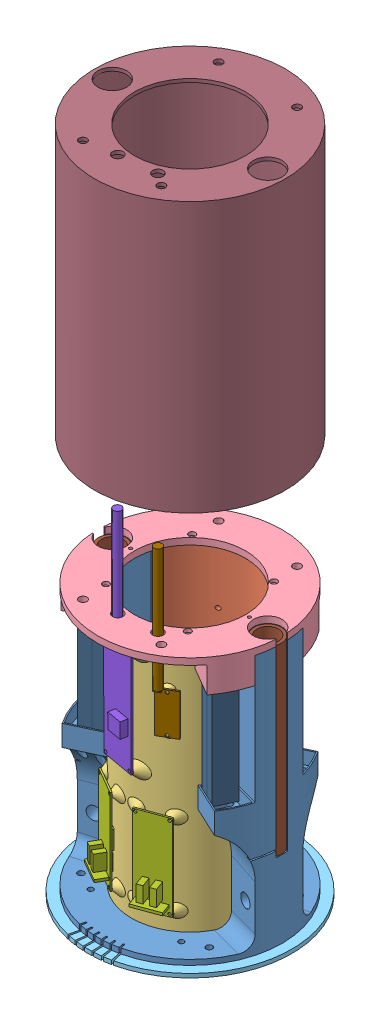
SolidWorks assembly Electronics Bay Assembly, configuration Default. Lengths in mm.
Overall size (198.12 649.43 198.12).
23 component instances, 13 part files, 55 mates.
Components (placement in the parent):
- Base 2-3: Base 2 [Default] at origin size (179.07 252.73 179.07)
- Recovery Slide ALARA-3: Recovery Slide ALARA [Default] at (0 5.08 0) size (111.51 248.38 47.72)
- Recovery Slide General-3: Recovery Slide General [Default] at (0 5.08 0) x (-1 0 0) z (0 0 -1) size (111.51 248.38 48.37)
- Top Part-7: Top Part [Default] at (0 259.08 0) x (-1 0 0) z (0 0 1) size (178.71 31.75 179.07)
- Centering Ring-3: Centering Ring [Baby Shark Recovery Centering Ring] at (0 -1.905 0) x (-1 0 0) z (0 0 -1) size (198.12 3.81 198.12)
- ALARA PCB-4: ALARA PCB [Default] at (25 60.255 -62.484) x (-1 0 0) z (0 1 0) size (50 1.52 150)
- Eggtimer Proton-6: Eggtimer Proton [Default] at (20.327 62.2633 55.9361) x (0 1 0) z (0.939693 0 -0.34202) size (83.27 15.04 30.57)
- Eggtimer Proton-7: Eggtimer Proton [Default] at (-29.7314 62.2633 51.5566) x (0 1 0) z (0.866025 0 0.5) size (83.27 15.04 30.57)
- Eggtimer TRS Tracker-9: Eggtimer TRS Tracker [Default] at (-10.3007 182.8899 58.6168) x (0.000689 -1 0.000122) z (-0.984808 -0.0007 -0.173648) size (216.46 11.11 32.77)
- Telemetry Module-5: Telemetry Module [Default] at (29.7575 190.5032 51.5415) x (0 -1 0) z (-0.866025 0 0.5) size (161.4 7.84 19.04)
- Turnigy nano-tech 1200mAh 2S 15_25C Lipo 2-13: Turnigy nano-tech 1200mAh 2S 15_25C Lipo 2 [Default] at (-46.5329 252.73 35.0242) x (-0.422618 0 -0.906308) z (0 1 0) size (19.71 10.41 127.79)
- Turnigy nano-tech 1200mAh 2S 15_25C Lipo 2-14: Turnigy nano-tech 1200mAh 2S 15_25C Lipo 2 [Default] at (-55.9712 252.73 39.4254) x (-0.422618 0 -0.906308) z (0 1 0) size (19.71 10.41 127.79)
- Turnigy nano-tech 1200mAh 2S 15_25C Lipo 2-15: Turnigy nano-tech 1200mAh 2S 15_25C Lipo 2 [Default] at (65.4095 252.73 43.8265) x (0.422618 0 -0.906308) z (0 1 0) size (19.71 10.41 127.79)
- Turnigy nano-tech 1200mAh 2S 15_25C Lipo 2-16: Turnigy nano-tech 1200mAh 2S 15_25C Lipo 2 [Default] at (55.9712 252.73 39.4254) x (0.422618 0 -0.906308) z (0 1 0) size (19.71 10.41 127.79)
- Charge Tube-1: Charge Tube [Default] at (75.565 74.93 0) x (0.797278 0 0.603612) z (-0.603612 0 0.797278) size (26.67 177.8 26.67)
- Charge Tube-2: Charge Tube [Default] at (-75.565 74.93 0) x (-0.785022 0 0.619467) z (-0.619467 0 -0.785022) size (26.67 177.8 26.67)
- Turnigy nano-tech 1200mAh 2S 15_25C Lipo 2-17: Turnigy nano-tech 1200mAh 2S 15_25C Lipo 2 [Default] at (-54.8629 252.73 -17.1605) x (0.422618 0 -0.906308) z (0 1 0) size (19.71 10.41 127.79)
- Turnigy nano-tech 1200mAh 2S 15_25C Lipo 2-18: Turnigy nano-tech 1200mAh 2S 15_25C Lipo 2 [Default] at (-64.3012 252.73 -21.5617) x (0.422618 0 -0.906308) z (0 1 0) size (19.71 10.41 127.79)
- Turnigy nano-tech 1200mAh 2S 15_25C Lipo 2-19: Turnigy nano-tech 1200mAh 2S 15_25C Lipo 2 [Default] at (73.7395 252.73 -25.9628) x (-0.422618 0 -0.906308) z (0 1 0) size (19.71 10.41 127.79)
- Turnigy nano-tech 1200mAh 2S 15_25C Lipo 2-20: Turnigy nano-tech 1200mAh 2S 15_25C Lipo 2 [Default] at (64.3012 252.73 -21.5617) x (-0.422618 0 -0.906308) z (0 1 0) size (19.71 10.41 127.79)
- 97171A310_Brass Heat-Set Inserts for Plastic-1: 97171A310_Brass Heat-Set Inserts for Plastic [97171A310] at (-23.7651 232.2195 53.378) x (0.661787 -0.740554 0.116691) z (-0.729304 -0.671996 -0.128596) size (5.54 6.42 5.54)
- 97171A310_Brass Heat-Set Inserts for Plastic-2: 97171A310_Brass Heat-Set Inserts for Plastic [97171A310] at (-39.7766 249.3298 41.9158) x (0.543007 0 -0.839728) z (0.839728 0 0.543007) size (5.54 6.42 5.54)
- Ebay Hatch V2-2: Ebay Hatch V2 [Default] at (0 645.6163 0) x (-1 0 0) z (0 0 1) size (185.42 262.38 185.42)
Mates (geometry in assembly coordinates):
- Coincident130: coincident anti-aligned: plane of Base 2-3 through (0 252.73 0) normal (0 1 0); plane of Top Part-7 through (0 252.73 0) normal (0 -1 0)
- Coincident131: coincident anti-aligned: plane of Base 2-3 through (0 252.73 0) normal (0.258819 0 -0.965926); plane of Top Part-7 through (0 227.33 0) normal (-0.258819 0 0.965926)
- Coincident132: coincident anti-aligned: plane of Base 2-3 through (0 0 0) normal (0 -1 0); plane of Centering Ring-3 through (0 0 0) normal (0 1 0)
- Concentric76: concentric anti-aligned: cylinder of Base 2-3 through (44.0824 -7.1842 52.5353) axis (0 1 0) radius 2.54; cylinder of Centering Ring-3 through (44.0824 8.621 52.5353) axis (0 -1 0) radius 2.54
- Concentric77: concentric anti-aligned: cylinder of Base 2-3 through (0 5.08 0) axis (0 -1 0) radius 89.535; cylinder of Centering Ring-3 through (0 -3.81 0) axis (0 1 0) radius 99.06
- Concentric78: concentric aligned: cylinder of Base 2-3 through (0 5.08 0) axis (0 -1 0) radius 53.975; cylinder of Recovery Slide General-3 through (0 252.73 0) axis (0 -1 0) radius 53.975
- Coincident133: coincident anti-aligned: plane of Base 2-3 through (0 252.73 0) normal (-0.258819 0 0.965926); plane of Recovery Slide General-3 through (0 252.73 0) normal (0.258819 0 -0.965926)
- Coincident134: coincident anti-aligned: plane of Recovery Slide General-3 through (0 252.73 0) normal (0 1 0); plane of Top Part-7 through (0 252.73 0) normal (0 -1 0)
- Concentric79: concentric anti-aligned: cylinder of Base 2-3 through (0 5.08 0) axis (0 -1 0) radius 89.535; cylinder of Top Part-7 through (0 252.73 0) axis (0 1 0) radius 89.535
- Concentric80: concentric aligned: cylinder of Base 2-3 through (0 5.08 0) axis (0 -1 0) radius 53.975; cylinder of Recovery Slide ALARA-3 through (0 252.73 0) axis (0 -1 0) radius 53.975
- Coincident135: coincident anti-aligned: plane of Base 2-3 through (0 252.73 0) normal (-0.258819 0 -0.965926); plane of Recovery Slide ALARA-3 through (0 252.73 0) normal (0.258819 0 0.965926)
- Coincident136: coincident anti-aligned: plane of Recovery Slide ALARA-3 through (0 252.73 0) normal (0 1 0); plane of Top Part-7 through (0 252.73 0) normal (0 -1 0)
- Coincident158: coincident anti-aligned: plane of Recovery Slide ALARA-3 through (-22 202.255 -60.96) normal (0 0 -1); plane of ALARA PCB-4 through (25 60.255 -60.96) normal (0 0 1)
- Concentric97: concentric anti-aligned: cylinder of Recovery Slide ALARA-3 through (22 202.255 -13.2433) axis (0 0 -1) radius 2.0193; cylinder of ALARA PCB-4 through (22 202.255 -67.0095) axis (0 0 1) radius 1.6
- Coincident159: coincident anti-aligned: plane of Recovery Slide General-3 through (-41.086 101.6 45.001) normal (-0.5 0 0.866025); plane of Eggtimer Proton-7 through (-29.7314 62.2633 51.5566) normal (0.5 0 -0.866025)
- Concentric98: concentric aligned: cylinder of Recovery Slide General-3 through (19.0385 22.86 -6.8136) axis (-0.5 0 0.866025) radius 2.0193; cylinder of Eggtimer Proton-7 through (-16.3568 22.86 54.4929) axis (-0.5 0 0.866025) radius 1.4653
- Coincident160: coincident anti-aligned: plane of Recovery Slide General-3 through (8.0632 101.6 60.3998) normal (0.34202 0 0.939693); plane of Eggtimer Proton-6 through (20.327 62.2633 55.9361) normal (-0.34202 0 -0.939693)
- Concentric99: concentric aligned: cylinder of Recovery Slide General-3 through (-14.2405 22.86 -0.8791) axis (0.34202 0 0.939693) radius 2.0193; cylinder of Eggtimer Proton-6 through (6.6457 22.86 56.5053) axis (0.34202 0 0.939693) radius 1.4653
- Coincident161: coincident anti-aligned: plane of Recovery Slide General-3 through (-24.255 232.2195 56.1563) normal (-0.173648 0 0.984808); plane of Eggtimer TRS Tracker-9 through (-10.3007 182.8899 58.6168) normal (0.173648 0 -0.984808)
- Concentric100: concentric aligned: cylinder of Recovery Slide General-3 through (-14.6497 232.2195 1.6815) axis (-0.173648 0 0.984808) radius 2.0193; cylinder of Eggtimer TRS Tracker-9 through (-23.5252 232.2195 52.0174) axis (-0.173648 0 0.984808) radius 1.4859
- Coincident163: coincident anti-aligned: plane of Recovery Slide General-3 through (29.7575 208.28 51.5415) normal (0.5 0 0.866025); plane of Telemetry Module-5 through (29.7575 190.5032 51.5415) normal (-0.5 0 -0.866025)
- Concentric101: concentric aligned: cylinder of Recovery Slide General-3 through (-7.71 208.28 -13.3541) axis (0.5 0 0.866025) radius 2.0193; cylinder of Telemetry Module-5 through (27.6696 208.28 47.9251) axis (0.5 0 0.866025) radius 1.4764
- Coincident164: coincident anti-aligned: plane of Turnigy nano-tech 1200mAh 2S 15_25C Lipo 2-13 through (-55.9712 252.73 39.4254) normal (-0.906308 0 0.422618); plane of Turnigy nano-tech 1200mAh 2S 15_25C Lipo 2-14 through (-55.9712 252.73 39.4254) normal (0.906308 0 -0.422618)
- Coincident165: coincident aligned: plane of Turnigy nano-tech 1200mAh 2S 15_25C Lipo 2-13 through (-55.9712 252.73 39.4254) normal (0.422618 0 0.906308); plane of Turnigy nano-tech 1200mAh 2S 15_25C Lipo 2-14 through (-65.4095 252.73 43.8265) normal (0.422618 0 0.906308)
- Coincident166: coincident aligned: plane of Turnigy nano-tech 1200mAh 2S 15_25C Lipo 2-13 through (-55.9712 252.73 39.4254) normal (0 1 0); plane of Turnigy nano-tech 1200mAh 2S 15_25C Lipo 2-14 through (-65.4095 252.73 43.8265) normal (0 1 0)
- Coincident167: coincident aligned: plane of Turnigy nano-tech 1200mAh 2S 15_25C Lipo 2-15 through (55.9712 252.73 39.4254) normal (-0.422618 0 0.906308); plane of Turnigy nano-tech 1200mAh 2S 15_25C Lipo 2-16 through (46.5329 252.73 35.0242) normal (-0.422618 0 0.906308)
- Coincident168: coincident anti-aligned: plane of Turnigy nano-tech 1200mAh 2S 15_25C Lipo 2-15 through (55.9712 252.73 39.4254) normal (-0.906308 0 -0.422618); plane of Turnigy nano-tech 1200mAh 2S 15_25C Lipo 2-16 through (55.9712 252.73 39.4254) normal (0.906308 0 0.422618)
- Coincident169: coincident aligned: plane of Turnigy nano-tech 1200mAh 2S 15_25C Lipo 2-15 through (55.9712 252.73 39.4254) normal (0 1 0); plane of Turnigy nano-tech 1200mAh 2S 15_25C Lipo 2-16 through (46.5329 252.73 35.0242) normal (0 1 0)
- Coincident170: coincident anti-aligned: plane of Top Part-7 through (0 252.73 0) normal (0 -1 0); plane of Turnigy nano-tech 1200mAh 2S 15_25C Lipo 2-13 through (-55.9712 252.73 39.4254) normal (0 1 0)
- Coincident171: coincident anti-aligned: plane of Top Part-7 through (-3.226 227.33 -6.9182) normal (0.422618 0 0.906308); plane of Turnigy nano-tech 1200mAh 2S 15_25C Lipo 2-13 through (-64.3012 252.73 21.5617) normal (-0.422618 0 -0.906308)
- Coincident172: coincident anti-aligned: plane of Top Part-7 through (0 252.73 0) normal (0 -1 0); plane of Turnigy nano-tech 1200mAh 2S 15_25C Lipo 2-15 through (55.9712 252.73 39.4254) normal (0 1 0)
- Tangent6: tangent anti-aligned: cylinder of Recovery Slide General-3 through (0 252.73 0) axis (0 -1 0) radius 56.975; plane of Turnigy nano-tech 1200mAh 2S 15_25C Lipo 2-13 through (-46.5329 252.73 35.0242) normal (0.906308 0 -0.422618)
- Coincident174: coincident anti-aligned: plane of Top Part-7 through (3.226 227.33 -6.9182) normal (-0.422618 0 0.906308); plane of Turnigy nano-tech 1200mAh 2S 15_25C Lipo 2-16 through (54.8629 252.73 17.1605) normal (0.422618 0 -0.906308)
- Tangent7: tangent anti-aligned: cylinder of Recovery Slide General-3 through (0 252.73 0) axis (0 -1 0) radius 56.975; plane of Turnigy nano-tech 1200mAh 2S 15_25C Lipo 2-16 through (46.5329 252.73 35.0242) normal (-0.906308 0 -0.422618)
- Concentric102: concentric anti-aligned: cylinder of Base 2-3 through (75.565 74.93 0) axis (0 1 0) radius 13.97; cylinder of Charge Tube-1 through (75.565 252.73 0) axis (0 -1 0) radius 13.335
- Coincident175: coincident anti-aligned: plane of Base 2-3 through (0 74.93 0) normal (0 1 0); plane of Charge Tube-1 through (75.565 74.93 0) normal (0 -1 0)
- Concentric103: concentric anti-aligned: cylinder of Base 2-3 through (-75.565 74.93 0) axis (0 1 0) radius 13.97; cylinder of Charge Tube-2 through (-75.565 252.73 0) axis (0 -1 0) radius 13.335
- Coincident176: coincident anti-aligned: plane of Base 2-3 through (0 74.93 0) normal (0 1 0); plane of Charge Tube-2 through (-75.565 74.93 0) normal (0 -1 0)
- Coincident177: coincident anti-aligned: plane of Turnigy nano-tech 1200mAh 2S 15_25C Lipo 2-17 through (-64.3012 252.73 -21.5617) normal (-0.906308 0 -0.422618); plane of Turnigy nano-tech 1200mAh 2S 15_25C Lipo 2-18 through (-64.3012 252.73 -21.5617) normal (0.906308 0 0.422618)
- Coincident178: coincident aligned: plane of Turnigy nano-tech 1200mAh 2S 15_25C Lipo 2-17 through (-64.3012 252.73 -21.5617) normal (-0.422618 0 0.906308); plane of Turnigy nano-tech 1200mAh 2S 15_25C Lipo 2-18 through (-73.7395 252.73 -25.9628) normal (-0.422618 0 0.906308)
- Coincident179: coincident aligned: plane of Turnigy nano-tech 1200mAh 2S 15_25C Lipo 2-17 through (-64.3012 252.73 -21.5617) normal (0 1 0); plane of Turnigy nano-tech 1200mAh 2S 15_25C Lipo 2-18 through (-73.7395 252.73 -25.9628) normal (0 1 0)
- Coincident180: coincident anti-aligned: plane of Top Part-7 through (-3.226 227.33 6.9182) normal (0.422618 0 -0.906308); plane of Turnigy nano-tech 1200mAh 2S 15_25C Lipo 2-17 through (-64.3012 252.73 -21.5617) normal (-0.422618 0 0.906308)
- Tangent8: tangent anti-aligned: cylinder of Recovery Slide ALARA-3 through (0 252.73 0) axis (0 -1 0) radius 56.975; plane of Turnigy nano-tech 1200mAh 2S 15_25C Lipo 2-17 through (-54.8629 252.73 -17.1605) normal (0.906308 0 0.422618)
- Coincident181: coincident anti-aligned: plane of Top Part-7 through (0 252.73 0) normal (0 -1 0); plane of Turnigy nano-tech 1200mAh 2S 15_25C Lipo 2-18 through (-73.7395 252.73 -25.9628) normal (0 1 0)
- Coincident182: coincident anti-aligned: plane of Turnigy nano-tech 1200mAh 2S 15_25C Lipo 2-19 through (64.3012 252.73 -21.5617) normal (-0.906308 0 0.422618); plane of Turnigy nano-tech 1200mAh 2S 15_25C Lipo 2-20 through (64.3012 252.73 -21.5617) normal (0.906308 0 -0.422618)
- Coincident183: coincident aligned: plane of Turnigy nano-tech 1200mAh 2S 15_25C Lipo 2-19 through (64.3012 252.73 -21.5617) normal (0.422618 0 0.906308); plane of Turnigy nano-tech 1200mAh 2S 15_25C Lipo 2-20 through (54.8629 252.73 -17.1605) normal (0.422618 0 0.906308)
- Coincident184: coincident aligned: plane of Turnigy nano-tech 1200mAh 2S 15_25C Lipo 2-19 through (64.3012 252.73 -21.5617) normal (0 1 0); plane of Turnigy nano-tech 1200mAh 2S 15_25C Lipo 2-20 through (54.8629 252.73 -17.1605) normal (0 1 0)
- Coincident185: coincident anti-aligned: plane of Top Part-7 through (3.226 227.33 6.9182) normal (-0.422618 0 -0.906308); plane of Turnigy nano-tech 1200mAh 2S 15_25C Lipo 2-20 through (54.8629 252.73 -17.1605) normal (0.422618 0 0.906308)
- Coincident186: coincident anti-aligned: plane of Top Part-7 through (0 252.73 0) normal (0 -1 0); plane of Turnigy nano-tech 1200mAh 2S 15_25C Lipo 2-20 through (54.8629 252.73 -17.1605) normal (0 1 0)
- Tangent9: tangent anti-aligned: cylinder of Recovery Slide ALARA-3 through (0 252.73 0) axis (0 -1 0) radius 56.975; plane of Turnigy nano-tech 1200mAh 2S 15_25C Lipo 2-20 through (54.8629 252.73 -17.1605) normal (-0.906308 0 0.422618)
- Concentric104: concentric aligned: cylinder of Recovery Slide General-3 through (-39.7766 231.7786 41.9158) axis (0 1 0) radius 2.0193; cylinder of 97171A310_Brass Heat-Set Inserts for Plastic-2 through (-39.7766 252.73 41.9158) axis (0 1 0) radius 1.9558
- Coincident187: coincident aligned: plane of Recovery Slide General-3 through (0 252.73 0) normal (0 1 0); plane of 97171A310_Brass Heat-Set Inserts for Plastic-2 through (-40.6725 252.73 43.3013) normal (0 1 0)
- Concentric106: concentric aligned: cylinder of Recovery Slide General-3 through (-14.6497 232.2195 1.6815) axis (-0.173648 0 0.984808) radius 2.0193; cylinder of 97171A310_Brass Heat-Set Inserts for Plastic-1 through (-24.3556 232.2195 56.7265) axis (-0.173648 0 0.984808) radius 1.9558
- Concentric109: concentric aligned: circle of Top Part-7; circle of Ebay Hatch V2-2
- Concentric110: concentric anti-aligned: cylinder of Top Part-7 through (38.1 269.8563 65.9911) axis (0 -1 0) radius 3.81; cylinder of Ebay Hatch V2-2 through (38.1 383.2343 65.9911) axis (0 1 0) radius 3.81
